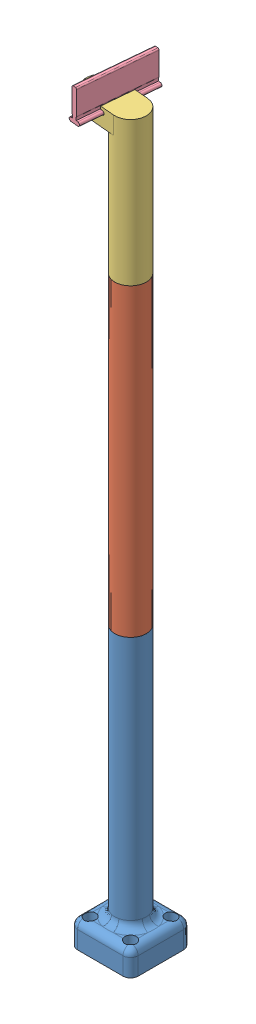
SolidWorks assembly camera support, configuration Default. Lengths in mm.
Overall size (62.48 595.2 60.57).
4 component instances, 4 part files, 7 mates.
Components (placement in the parent):
- camera support-1: camera support [Default] at (121.3496 36.8727 151.7242) size (48 232 48)
- camera support long-1: camera support long [Default] at (121.3496 236.8727 151.7242) x (0.999706 0 0.024259) z (-0.024259 0 0.999706) size (25 253 25)
- camera support base-1: camera support base [Default] at (121.3496 477.8727 151.7242) x (0.091136 0 -0.995838) z (0.995838 0 0.091136) size (25 114 50)
- camera fix-1: camera fix [Default] at (110.9884 589.0727 120.6506) x (0.995838 0 0.091136) z (-0.091136 0 0.995838) size (9 25.5 60)
Mates (geometry in assembly coordinates):
- Coincident2: coincident anti-aligned: plane of camera support-1 through (121.3496 236.8727 151.7242) normal (0 1 0); plane of camera support long-1 through (121.3496 236.8727 151.7242) normal (0 -1 0)
- Concentric1: concentric aligned: cylinder of camera support-1 through (121.3496 236.8727 151.7242) axis (0 -1 0) radius 12.5; cylinder of camera support long-1 through (121.3496 477.8727 151.7242) axis (0 -1 0) radius 12.5
- Concentric2: concentric aligned: cylinder of camera support long-1 through (121.3496 477.8727 151.7242) axis (0 -1 0) radius 12.5; cylinder of camera support base-1 through (121.3496 577.8727 151.7242) axis (0 -1 0) radius 12.5
- Coincident7: coincident anti-aligned: plane of camera support long-1 through (121.3496 477.8727 151.7242) normal (0 1 0); plane of camera support base-1 through (121.3496 477.8727 151.7242) normal (0 -1 0)
- Distance1: distance = 17.5 mm aligned: plane of camera fix-1 through (105.5203 589.0727 180.4009) normal (-0.091136 0 0.995838); plane of camera support base-1 through (120.2104 591.8727 164.1722) normal (-0.091136 0 0.995838)
- Distance4: distance = 0.15 mm anti-aligned: plane of camera support base-1 through (104.466 589.7227 173.8166) normal (0 -1 0); plane of camera fix-1 through (109.2236 589.5727 107.0167) normal (0 1 0)
- Distance5: distance = 0.15 mm anti-aligned: plane of camera fix-1 through (110.7174 592.0727 107.1534) normal (-0.995838 0 -0.091136); plane of camera support base-1 through (104.466 591.8727 173.8166) normal (0.995838 0 0.091136)
